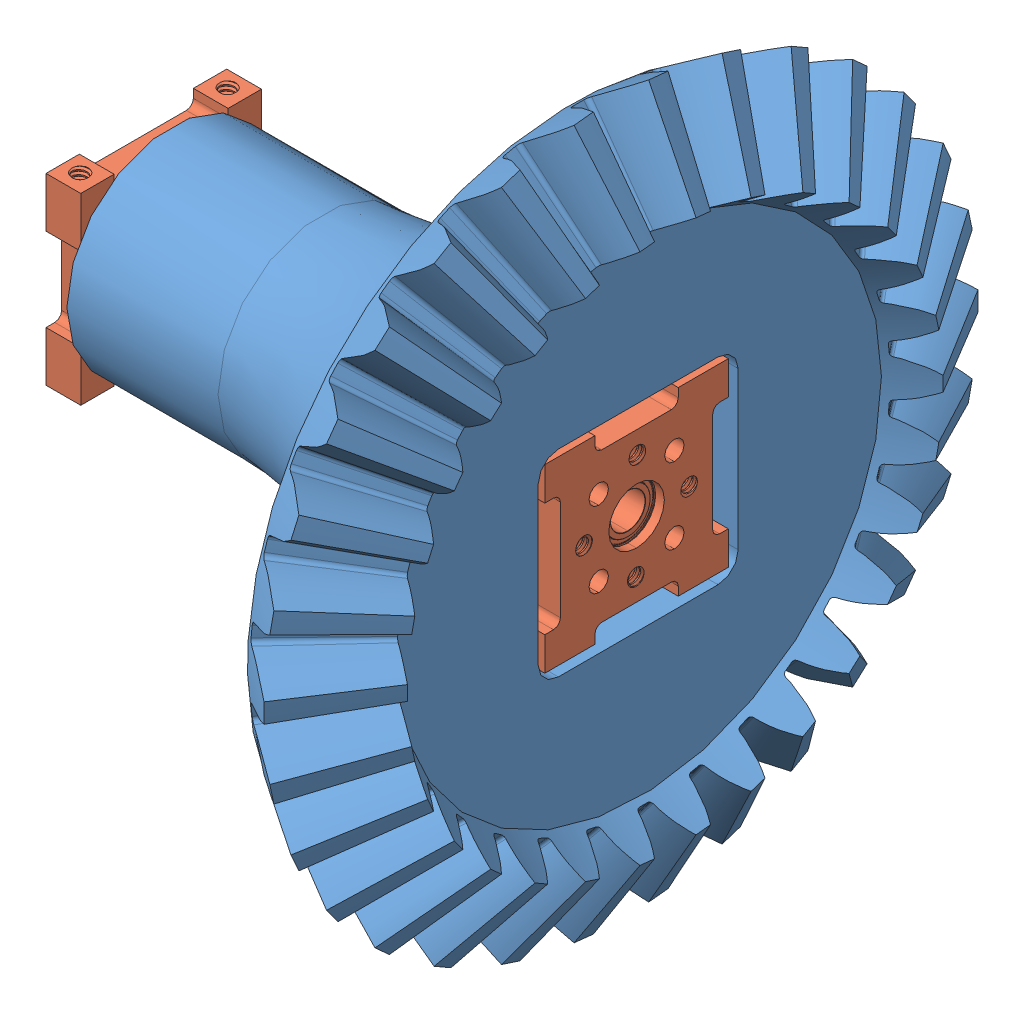
SolidWorks assembly ARMUS-103-400, configuration Défaut. Lengths in mm.
Overall size (128.27 130.43 130.79).
3 component instances, 2 part files, 8 mates.
Components (placement in the parent):
- ARMUS-REV4-401-1: ARMUS-REV4-401 [Default] at origin size (93.2 130.43 130.79)
- Bore Side Tapped Pillow Block 1.25-1: Bore Side Tapped Pillow Block 1.25 [Default] at (-58.9626 7.6184 28.3917) x (0 -1 0) z (0 0 -1) size (33.54 6.35 33.02)
- Bore Side Tapped Pillow Block 1.25-2: Bore Side Tapped Pillow Block 1.25 [Default] at (26.0822 -28.3917 7.6184) x (0 0 -1) z (0 1 0) size (33.54 6.35 33.02)
Mates (geometry in assembly coordinates):
- Concentric294: concentric anti-aligned: cylinder of ARMUS-REV4-401-1 through (128.2701 0 0) axis (-1 0 0) radius 6.35; cylinder of Bore Side Tapped Pillow Block 1.25-2 through (5.5295 0 0) axis (1 0 0) radius 3.175
- Concentric296: concentric anti-aligned: cylinder of ARMUS-REV4-401-1 through (5.5168 -6.9148 -6.9148) axis (1 0 0) radius 1.25; cylinder of Bore Side Tapped Pillow Block 1.25-2 through (5.5168 -6.9148 -6.9148) axis (-1 0 0) radius 1.778
- Concentric297: concentric anti-aligned: cylinder of ARMUS-REV4-401-1 through (5.5168 6.9148 -6.9148) axis (1 0 0) radius 1.25; cylinder of Bore Side Tapped Pillow Block 1.25-2 through (5.5168 6.9148 -6.9148) axis (-1 0 0) radius 1.778
- Coincident59: coincident anti-aligned: plane of ARMUS-REV4-401-1 through (5.5168 0 0) normal (1 0 0); plane of Bore Side Tapped Pillow Block 1.25-2 through (5.5168 0 0) normal (-1 0 0)
- Coincident60: coordinate: point of ARMUS-REV4-401-1
- Concentric299: concentric anti-aligned: cylinder of ARMUS-REV4-401-1 through (5.5168 -6.9148 -6.9148) axis (1 0 0) radius 1.25; cylinder of Bore Side Tapped Pillow Block 1.25-1 through (-79.5281 -6.9148 -6.9148) axis (-1 0 0) radius 1.778
- Coincident61: coincident anti-aligned: plane of ARMUS-REV4-401-1 through (-73.1781 -65.2174 -19.05) normal (-1 0 0); plane of Bore Side Tapped Pillow Block 1.25-1 through (-73.1781 0 0) normal (1 0 0)
- Concentric301: concentric anti-aligned: cylinder of ARMUS-REV4-401-1 through (5.5168 6.9148 6.9148) axis (1 0 0) radius 1.25; cylinder of Bore Side Tapped Pillow Block 1.25-1 through (-79.5281 6.9148 6.9148) axis (-1 0 0) radius 1.778
